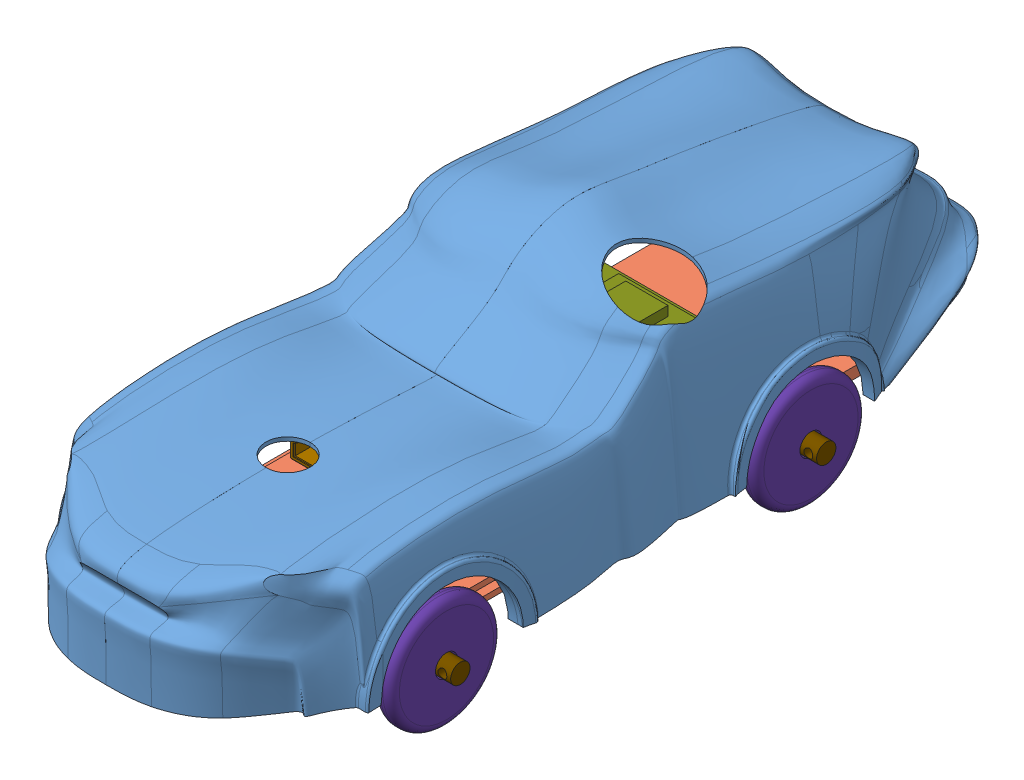
SolidWorks assembly Assemblage finale, configuration Défaut. Lengths in mm.
Overall size (121 105.93 291.64).
52 component instances, 19 part files, 29 mates.
Components (placement in the parent):
- Coqueavant-1: Coqueavant [Default] at (-14.0618 24.6276 330.2812) size (118.53 105.93 291.64)
- Assemblage socle rasp-1: Assemblage socle rasp [Défaut] at (-3.3632 -253.3724 303.5208) x (0 0 1) z (0 1 0) size (230 81 35.51)
  - socle-1: socle [Défaut] at (-121.8936 -48.2005 229) size (230 81 4)
  - raspberry_avec_fixation-1: raspberry_avec_fixation [Défaut] at (0.2796 -19.1067 160.5275) size (88.15 58.67 24.6)
    - raspberry_carte-1: raspberry_carte [Défaut] at (3.2718 1.1337 -17.039) size (87.37 58 19.41)
      - carte_mere-1: carte_mere [Défaut] at (-80.1391 -196.9883 96.5115) size (83.14 55 7)
      - HDMI_socket-1: HDMI_socket [Default] at (-19.1396 -14.9354 101.6365) x (1 0 0) z (0 -1 0) size (16.2 8 9.9)
        - HDMI_socket_cover-1: HDMI_socket_cover [Default] at (-20 0 0) size (16.2 8 9)
        - HDMI_socket_inside-1: HDMI_socket_inside [Default] at (-20 0 0) size (15 6.1 7.6)
        - HDMI_socket_large_pin-1: HDMI_socket_large_pin [Valor predeterminado] at (-201.7661 0.45 76.5103) x (0 0 -1) z (0 -1 0) size (7.55 0.65 3.84)
        - HDMI_socket_small_pin-1: HDMI_socket_small_pin [Valor predeterminado] at (-202.2661 -0.25 76.5103) x (0 0 -1) z (0 -1 0) size (7.55 0.65 3.08)
        - HDMI_socket_large_pin-2: HDMI_socket_large_pin [Valor predeterminado] at (-202.7661 0.45 76.5103) x (0 0 -1) z (0 -1 0) size (7.55 0.65 3.84)
        - HDMI_socket_large_pin-3: HDMI_socket_large_pin [Valor predeterminado] at (-203.7661 0.45 76.5103) x (0 0 -1) z (0 -1 0) size (7.55 0.65 3.84)
        - HDMI_socket_large_pin-4: HDMI_socket_large_pin [Valor predeterminado] at (-204.7661 0.45 76.5103) x (0 0 -1) z (0 -1 0) size (7.55 0.65 3.84)
        - HDMI_socket_large_pin-5: HDMI_socket_large_pin [Valor predeterminado] at (-205.7661 0.45 76.5103) x (0 0 -1) z (0 -1 0) size (7.55 0.65 3.84)
        - HDMI_socket_large_pin-6: HDMI_socket_large_pin [Valor predeterminado] at (-206.7661 0.45 76.5103) x (0 0 -1) z (0 -1 0) size (7.55 0.65 3.84)
        - HDMI_socket_large_pin-7: HDMI_socket_large_pin [Valor predeterminado] at (-207.7661 0.45 76.5103) x (0 0 -1) z (0 -1 0) size (7.55 0.65 3.84)
        - HDMI_socket_large_pin-8: HDMI_socket_large_pin [Valor predeterminado] at (-208.7661 0.45 76.5103) x (0 0 -1) z (0 -1 0) size (7.55 0.65 3.84)
        - HDMI_socket_large_pin-9: HDMI_socket_large_pin [Valor predeterminado] at (-209.7661 0.45 76.5103) x (0 0 -1) z (0 -1 0) size (7.55 0.65 3.84)
        - HDMI_socket_large_pin-10: HDMI_socket_large_pin [Valor predeterminado] at (-210.7661 0.45 76.5103) x (0 0 -1) z (0 -1 0) size (7.55 0.65 3.84)
        - HDMI_socket_small_pin-2: HDMI_socket_small_pin [Valor predeterminado] at (-203.2661 -0.25 76.5103) x (0 0 -1) z (0 -1 0) size (7.55 0.65 3.08)
        - HDMI_socket_small_pin-3: HDMI_socket_small_pin [Valor predeterminado] at (-204.2661 -0.25 76.5103) x (0 0 -1) z (0 -1 0) size (7.55 0.65 3.08)
        - HDMI_socket_small_pin-4: HDMI_socket_small_pin [Valor predeterminado] at (-205.2661 -0.25 76.5103) x (0 0 -1) z (0 -1 0) size (7.55 0.65 3.08)
        - HDMI_socket_small_pin-5: HDMI_socket_small_pin [Valor predeterminado] at (-206.2661 -0.25 76.5103) x (0 0 -1) z (0 -1 0) size (7.55 0.65 3.08)
        - HDMI_socket_small_pin-6: HDMI_socket_small_pin [Valor predeterminado] at (-207.2661 -0.25 76.5103) x (0 0 -1) z (0 -1 0) size (7.55 0.65 3.08)
        - HDMI_socket_small_pin-7: HDMI_socket_small_pin [Valor predeterminado] at (-208.2661 -0.25 76.5103) x (0 0 -1) z (0 -1 0) size (7.55 0.65 3.08)
        - HDMI_socket_small_pin-8: HDMI_socket_small_pin [Valor predeterminado] at (-209.2661 -0.25 76.5103) x (0 0 -1) z (0 -1 0) size (7.55 0.65 3.08)
        - HDMI_socket_small_pin-9: HDMI_socket_small_pin [Valor predeterminado] at (-210.2661 -0.25 76.5103) x (0 0 -1) z (0 -1 0) size (7.55 0.65 3.08)
      - usb3x2-1: usb3x2 [Default] at (36.3042 19.0646 97.9115) x (0 0 1) z (0 -1 0) size (19.41 17.47 15.68)
      - usb3x2-2: usb3x2 [Default] at (36.3042 -0.0354 97.9115) x (0 0 1) z (0 -1 0) size (19.41 17.47 15.68)
      - RJ45_10P_TJ3009-1: RJ45_10P_TJ3009 [Default] at (24.681 -11.8354 98.5122) x (0 1 0) z (1 0 0) size (16 15.87 21.5)
      - PCB_Stereo_Jack_(assembly)-1: PCB_Stereo_Jack_(assembly) [Default] at (63.1833 -148.0042 87.2849) x (0 -1 0) z (-1 0 0) size (14.3 8.75 6.5)
        - PCB_Stereo_Jack_(body)-1: PCB_Stereo_Jack_(body) [Default] at (-133.6188 11.2266 60.3273) size (14.3 6.5 6.5)
        - PCB_Stereo_Jack_(GND_contact)-1: PCB_Stereo_Jack_(GND_contact) [Default] at (-127.9388 11.9766 60.3273) x (0 0 1) z (-1 0 0) size (5.5 8.75 2.58)
        - PCB_Stereo_Jack_(channel_contact_2)-1: PCB_Stereo_Jack_(channel_contact_2) [Default] at (-135.1188 11.9766 60.3273) x (0 0 1) z (-1 0 0) size (5.5 8.75 2.75)
        - PCB_Stereo_Jack_(channel_contact_1)-1: PCB_Stereo_Jack_(channel_contact_1) [Default] at (-131.2388 11.9766 60.3273) x (0 0 1) z (-1 0 0) size (5.5 8.75 2.58)
      - USB-1: USB [Default] at (-40.684 -2.2354 98.5115) x (0 -1 0) z (1 0 0) size (7.05 4.95 8)
    - Pièce espacement raspberry pi-1: Pièce espacement raspberry pi [Défaut] at (12.6178 32.2912 72.4725) x (1 0 0) z (0 -1 0) size (6 7 6)
    - Pièce espacement raspberry pi-2: Pièce espacement raspberry pi [Défaut] at (-44.1732 -15.4938 72.4725) x (0.932205 0.361932 0) z (0.361932 -0.932205 0) size (6 7 6)
    - Pièce espacement raspberry pi-3: Pièce espacement raspberry pi [Défaut] at (-44.1732 32.4014 72.4725) x (0.560382 -0.828234 0) z (-0.828234 -0.560382 0) size (6 7 6)
    - Pièce espacement raspberry pi-4: Pièce espacement raspberry pi [Défaut] at (12.4716 -15.5643 72.4725) x (1 0 0) z (0 -1 0) size (6 7 6)
  - vehicle electronics-1: vehicle electronics [Défaut] at (45.9412 -113.6823 250.3115) x (-0.000187 1 0) z (0 0 1) size (57.18 86.51 17.7)
- Wheel-1: Wheel [Défaut] at (41.4363 -22.2724 368.4773) x (0 0.904785 -0.425868) z (-1 0 0) size (40 40 7.05)
- Arbre-1: Arbre [Défaut] at (46.4363 -22.2724 368.4773) x (0 1 0) z (-1 0 0) size (8 8 40)
- Wheel-2: Wheel [Défaut] at (37.9363 -22.4724 233.3273) x (0 -0.509066 0.860728) z (-1 0 0) size (40 40 7.05)
- Wheel-3: Wheel [Défaut] at (-59.0637 -22.4724 234.6273) x (0 -0.501202 0.86533) z (-1 0 0) size (40 40 7.05)
- Wheel-4: Wheel [Défaut] at (-62.5637 -22.2724 368.4773) x (0 -0.460744 0.887533) z (-1 0 0) size (40 40 7.05)
- Arbre-2: Arbre [Défaut] at (43.4363 -22.4724 233.3273) x (0 -1 0) z (-1 0 0) size (8 8 40)
- Arbre-3: Arbre [Défaut] at (-74.5637 -22.2724 368.4773) x (0 -1 0) z (1 0 0) size (8 8 40)
- Arbre-4: Arbre [Défaut] at (-71.5637 -22.4724 234.6273) x (0 -1 0) z (1 0 0) size (8 8 40)
- Support socle-1: Support socle [Défaut] at (-44.0637 -28.3724 306.6273) x (1 0 0) z (0 1 0) size (56 40 4)
- Support socle-2: Support socle [Défaut] at (-44.0637 -20.3724 306.6273) x (1 0 0) z (0 1 0) size (56 40 4)
Mates (geometry in assembly coordinates):
- Coincident5: coincident anti-aligned: plane of Coqueavant-1 through (10.7798 -20.3724 187.5439) normal (0 -1 0); plane of Assemblage socle rasp-1/socle-1 through (-51.5637 -20.3724 181.6273) normal (0 1 0)
- Concentric1: concentric anti-aligned: cylinder of Coqueavant-1 through (21.8363 -20.3724 392.7973) axis (0 1 0) radius 1; cylinder of Assemblage socle rasp-1/socle-1 through (21.8363 -20.3724 392.7973) axis (0 -1 0) radius 1.1
- Parallel3: parallel anti-aligned: plane of Coqueavant-1 through (-66.0618 -22.3824 397.6896) normal (1 0 0); plane of Assemblage socle rasp-1/socle-1 through (-54.5637 -22.3724 406.6273) normal (-1 0 0)
- Concentric4: concentric anti-aligned: cylinder of Wheel-1 through (41.4363 -22.2724 368.4773) axis (-1 0 0) radius 4; cylinder of Arbre-1 through (26.4363 -22.2724 368.4773) axis (1 0 0) radius 3.5
- Distance3: distance = 5 mm aligned: plane of Arbre-1 through (46.4363 -22.2724 368.4773) normal (1 0 0); plane of Wheel-1 through (41.4363 -22.2724 368.4773) normal (1 0 0)
- Concentric6: concentric anti-aligned: cylinder of Wheel-2 through (37.9363 -22.4724 233.3273) axis (-1 0 0) radius 4; cylinder of Arbre-2 through (23.4363 -22.4724 233.3273) axis (1 0 0) radius 3.5
- Distance5: distance = 5.5 mm aligned: plane of Wheel-2 through (37.9363 -22.4724 233.3273) normal (1 0 0); plane of Arbre-2 through (43.4363 -22.4724 233.3273) normal (1 0 0)
- Concentric7: concentric aligned: cylinder of Wheel-3 through (-59.0637 -22.4724 234.6273) axis (-1 0 0) radius 4; cylinder of Arbre-4 through (-51.5637 -22.4724 234.6273) axis (-1 0 0) radius 3.5
- Distance7: distance = 5.5 mm aligned: plane of Wheel-3 through (-66.0637 -22.4724 234.6273) normal (-1 0 0); plane of Arbre-4 through (-71.5637 -22.4724 234.6273) normal (-1 0 0)
- Concentric8: concentric aligned: cylinder of Wheel-4 through (-62.5637 -22.2724 368.4773) axis (-1 0 0) radius 4; cylinder of Arbre-3 through (-54.5637 -22.2724 368.4773) axis (-1 0 0) radius 3.5
- Distance9: distance = 5 mm aligned: plane of Wheel-4 through (-69.5637 -22.2724 368.4773) normal (-1 0 0); plane of Arbre-3 through (-74.5637 -22.2724 368.4773) normal (-1 0 0)
- Coincident27: coincident anti-aligned: plane of Assemblage socle rasp-1/socle-1 through (-51.5637 -24.3724 181.6273) normal (0 -1 0); plane of Support socle-1 through (-44.0637 -24.3724 306.6273) normal (0 1 0)
- Coincident30: coincident anti-aligned: plane of Assemblage socle rasp-1/socle-1 through (-51.5637 -20.3724 181.6273) normal (0 1 0); plane of Support socle-2 through (-44.0637 -20.3724 306.6273) normal (0 -1 0)
- Coincident31: coincident anti-aligned: cylinder of Assemblage socle rasp-1/socle-1 through (3.4363 -20.3724 271.6273) axis (0 -1 0) radius 1.5; circle of Support socle-2
- Concentric9: concentric anti-aligned: cylinder of Assemblage socle rasp-1/socle-1 through (-31.5637 -20.3724 271.6273) axis (0 -1 0) radius 1.5; cylinder of Support socle-2 through (-31.5637 -20.3724 271.6273) axis (0 1 0) radius 1.5
- Coincident32: coincident aligned: cylinder of Support socle-1 through (-31.5637 -28.3724 271.6273) axis (0 1 0) radius 1.5; circle of Support socle-2
- Concentric10: concentric aligned: cylinder of Support socle-1 through (-14.0637 -28.3724 301.6273) axis (0 1 0) radius 1.5; cylinder of Support socle-2 through (-14.0637 -20.3724 301.6273) axis (0 1 0) radius 1.5
- Coincident33: coincident anti-aligned: plane of Assemblage socle rasp-1/socle-1 through (-51.5637 -20.3724 181.6273) normal (-1 0 0); plane of Arbre-4 through (-51.5637 -22.4724 234.6273) normal (1 0 0)
- Coincident34: coincident anti-aligned: plane of Assemblage socle rasp-1/socle-1 through (-51.5637 -20.3724 181.6273) normal (0 1 0); plane of Arbre-4 through (-51.5637 -20.3724 238.6273) normal (0 -1 0)
- Distance11: distance = 49 mm aligned: plane of Arbre-4 through (-31.5637 -18.4724 230.6273) normal (0 0 -1); plane of Assemblage socle rasp-1/socle-1 through (-51.5637 -20.3724 181.6273) normal (0 0 -1)
- Coincident36: coincident anti-aligned: plane of Assemblage socle rasp-1/socle-1 through (26.4363 -22.3724 406.6273) normal (1 0 0); plane of Arbre-1 through (26.4363 -22.2724 368.4773) normal (-1 0 0)
- Coincident37: coincident anti-aligned: plane of Assemblage socle rasp-1/socle-1 through (-51.5637 -24.3724 181.6273) normal (0 -1 0); plane of Arbre-1 through (26.4363 -24.3724 372.4773) normal (0 1 0)
- Concentric11: concentric aligned: cylinder of Assemblage socle rasp-1/socle-1 through (22.9363 -14.3724 367.6773) axis (0 -1 0) radius 1.6; cylinder of Arbre-1 through (22.9363 -18.2724 367.6773) axis (0 -1 0) radius 1.6
- Coincident38: coincident anti-aligned: plane of Assemblage socle rasp-1/socle-1 through (-54.5637 -22.3724 406.6273) normal (-1 0 0); plane of Arbre-3 through (-54.5637 -22.2724 368.4773) normal (1 0 0)
- Coincident39: coincident anti-aligned: plane of Assemblage socle rasp-1/socle-1 through (-51.5637 -24.3724 181.6273) normal (0 -1 0); plane of Arbre-3 through (-54.5637 -24.3724 372.4773) normal (0 1 0)
- Concentric12: concentric anti-aligned: cylinder of Assemblage socle rasp-1/socle-1 through (-41.0637 -20.3724 367.6773) axis (0 -1 0) radius 1.5; cylinder of Arbre-3 through (-41.0637 -26.2724 367.6773) axis (0 1 0) radius 1.6
- Coincident40: coincident anti-aligned: plane of Assemblage socle rasp-1/socle-1 through (23.4363 -20.3724 181.6273) normal (1 0 0); plane of Arbre-2 through (23.4363 -22.4724 233.3273) normal (-1 0 0)
- Coincident41: coincident anti-aligned: plane of Assemblage socle rasp-1/socle-1 through (-51.5637 -20.3724 181.6273) normal (0 1 0); plane of Arbre-2 through (23.4363 -20.3724 229.3273) normal (0 -1 0)
- Concentric13: concentric anti-aligned: cylinder of Assemblage socle rasp-1/socle-1 through (19.9363 -14.3724 234.1273) axis (0 -1 0) radius 1.5; cylinder of Arbre-2 through (19.9363 -26.4724 234.1273) axis (0 1 0) radius 1.6
